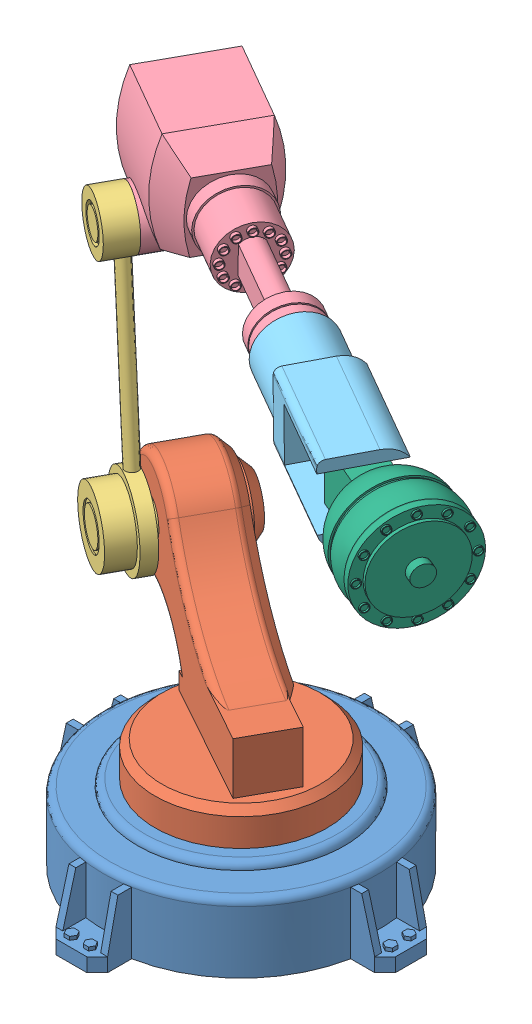
SolidWorks assembly Assem1, configuration Default. Lengths in mm.
Overall size (208.73 205.57 132.7).
6 component instances, 6 part files, 10 mates.
Components (placement in the parent):
- part 1-1: part 1 [Default] at (27.6504 43.1212 146.8723) size (145.28 33.02 125.2)
- part 2-1: part 2 [Default] at (24.4342 71.0612 143.5324) x (-0.875057 0 -0.484019) z (0.484019 0 -0.875057) size (101.6 69.85 63.5)
- part 3-2: part 3 [Default] at (-26.0535 121.8311 129.3939) x (-0.867184 -0.133844 -0.479664) z (-0.117121 0.991002 -0.064783) size (30.48 16.51 114.3)
- Part 4-1: Part 4 [Default] at (-39.796 229.6654 100.0225) x (0.874122 -0.04623 0.483502) z (-0.484019 0 0.875057) size (104.77 48.26 37.66)
- Part 5-1: Part 5 [Default] at (71.7726 223.7648 161.7343) x (-0.874122 0.04623 -0.483502) z (0.031508 0.99876 0.038533) size (67.84 25.4 28.96)
- Part 6-3: Part 6 [Default] at (113.541 221.627 182.9898) x (0.031508 0.99876 0.038533) z (0.928725 -0.043505 0.368209) size (39.56 39.56 52.92)
Mates (geometry in assembly coordinates):
- Coincident2: coincident anti-aligned: circle of part 1-1; circle of part 2-1
- Parallel3: parallel anti-aligned: plane of part 2-1 through (-23.3995 121.8612 125.0565) normal (-0.484019 0 0.875057); plane of part 3-2 through (-24.629 121.8612 127.2792) normal (0.484019 0 -0.875057)
- Concentric3: concentric anti-aligned: cylinder of part 2-1 through (-24.629 121.8612 127.2792) axis (0.484019 0 -0.875057) radius 19.05; cylinder of part 3-2 through (-24.629 121.8612 127.2792) axis (-0.484019 0 0.875057) radius 6.35
- Coincident7: coincident anti-aligned: circle of part 2-1; circle of part 3-2
- Coincident11: coincident anti-aligned: plane of part 3-2 through (-35.5435 209.9312 121.9677) normal (0.484019 0 -0.875057); plane of Part 4-1 through (-35.5435 209.9312 121.9677) normal (-0.484019 0 0.875057)
- Coincident12: coincident anti-aligned: circle of part 3-2; cylinder of Part 4-1 through (-35.5435 209.9312 121.9677) axis (-0.484019 0 0.875057) radius 5.715
- Coincident13: coincident anti-aligned: circle of Part 4-1; plane of Part 5-1 through (48.4597 224.9977 148.8393) normal (-0.874122 0.04623 -0.483502)
- Coincident14: coincident aligned: circle of Part 4-1; cylinder of Part 5-1 through (48.4597 224.9977 148.8393) axis (0.874122 -0.04623 0.483502) radius 6.35
- Coincident18: coincident anti-aligned: plane of Part 5-1 through (101.3781 210.51 177.8633) normal (0.031508 0.99876 0.038533); plane of Part 6-3 through (101.3781 210.51 177.8633) normal (-0.031508 -0.99876 -0.038533)
- Concentric11: concentric aligned: cylinder of Part 5-1 through (101.3781 210.51 177.8633) axis (0.031508 0.99876 0.038533) radius 5.08; cylinder of Part 6-3 through (101.3781 210.51 177.8633) axis (0.031508 0.99876 0.038533) radius 5.08
